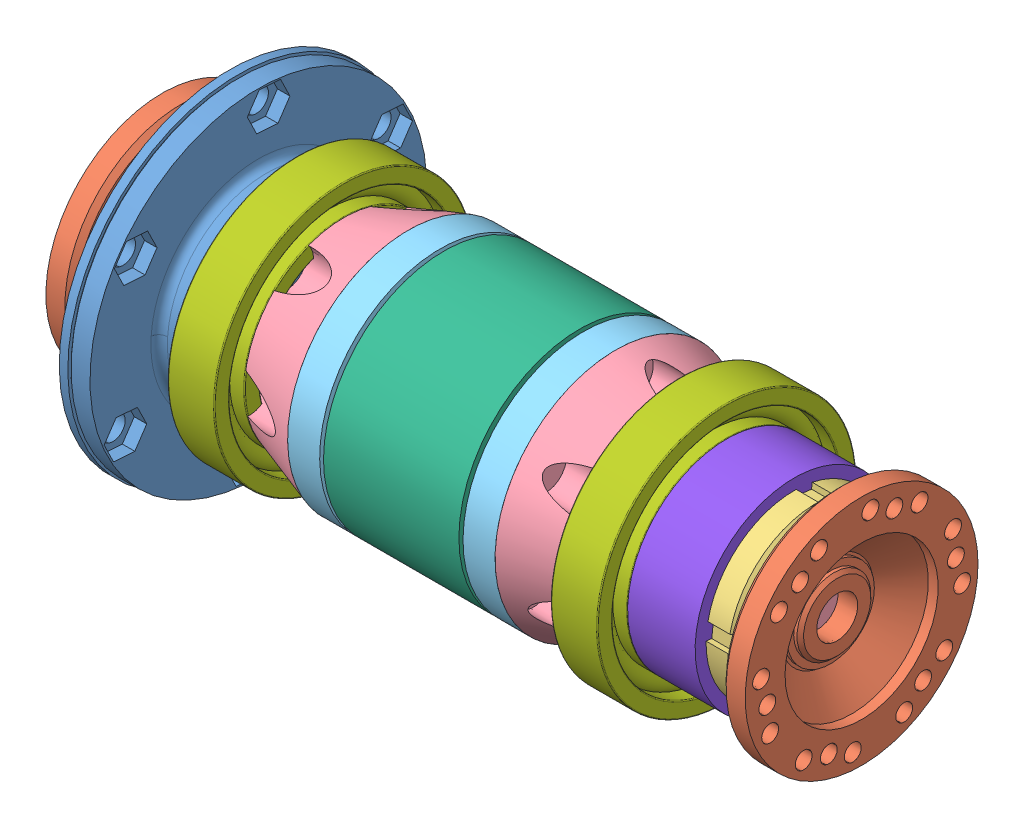
SolidWorks assembly quaife, configuration Default. Lengths in mm.
Overall size (270.26 241.3 241.3).
13 component instances, 8 part files, 0 mates.
Components (placement in the parent):
- DAA107x-1: DAA107x [Default] at (110.5343 226.8851 124.6281) x (1 0 0) z (0 0.069526 0.99758) size (40.89 131.67 131.67)
- DAA105-1: DAA105 [Default] at (-110.0707 -258.8556 -1.6643) x (-1 0 0) z (0 -0.546616 0.837384) size (17.38 89.97 89.97)
- DAA104-1: DAA104 [Default] at (-111.7408 245.6703 -81.5787) x (-1 0 0) z (0 0.248643 -0.968595) size (12.7 67.91 67.91)
- DAA104-2: DAA104 [Default] at (111.7408 232.0553 114.7141) x (1 0 0) z (0 0.11254 0.993647) size (12.7 67.91 67.91)
- DAA105-2: DAA105 [Default] at (110.0707 229.093 120.5213) x (1 0 0) z (0 0.087483 0.996166) size (17.38 89.97 89.97)
- daa101-1: daa101 [Default] at (110.5343 257.6984 24.5051) x (1 0 0) z (0 0.459188 0.888339) size (78.03 93.22 93.22)
- DAA102-1: DAA102 [Default] at (-110.5343 -50.3551 -253.916) x (-1 0 0) z (0 -0.930099 -0.367309) size (12.38 93.22 93.22)
- DAA106-1: DAA106 [Default] at (110.4218 -132.5606 222.3436) x (1 0 0) z (0 -0.999413 0.034263) size (62.48 93.22 93.22)
- daa101-2: daa101 [Default] at (-110.5343 -46.3671 -254.6745) x (-1 0 0) z (0 -0.924225 -0.381849) size (78.03 93.22 93.22)
- DAA102-2: DAA102 [Default] at (110.5343 -126.8259 -225.6638) x (1 0 0) z (0 0.467879 -0.883793) size (12.38 93.22 93.22)
- DAA103-1: DAA103 [Default] at (74.1299 -3.2907 140.0622) x (1 0 0) z (0 -0.023488 0.999724) size (18 100 100)
- DAA103-2: DAA103 [Default] at (-73.9089 21.8066 138.3933) x (1 0 0) z (0 0.155649 0.987812) size (18 100 100)
- DAA107y-1: DAA107y [Default] at (-110.5343 -64.4395 -250.712) x (-1 0 0) z (0 -0.949139 -0.314858) size (40.89 76.67 76.67)
